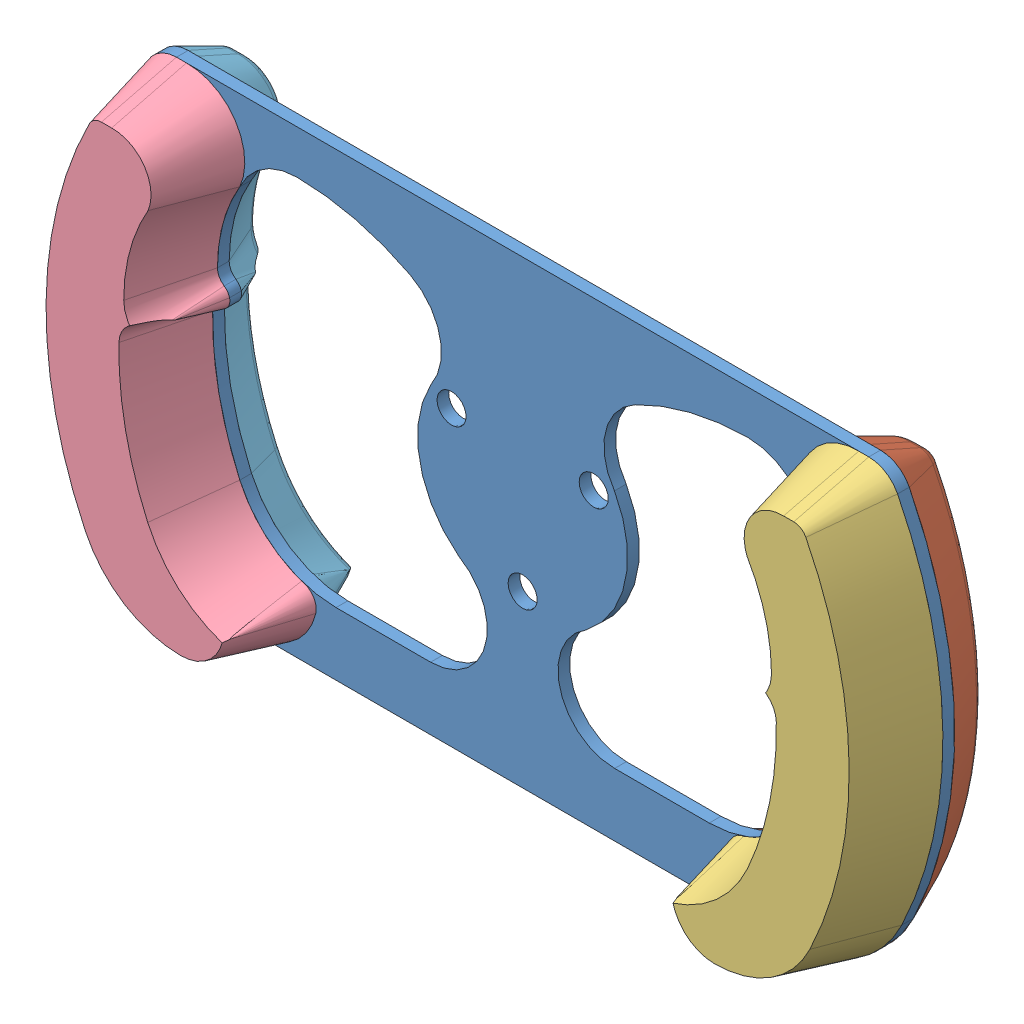
SolidWorks assembly FS2-ST-SW-A-V1, Steering Wheel, configuration Default. Lengths in mm.
Overall size (227.66 124.53 37.28).
5 component instances, 5 part files, 4 mates.
Components (placement in the parent):
- FS2-ST-SW-P-0001-V2, Steering Wheel center Structure-1: FS2-ST-SW-P-0001-V2, Steering Wheel center Structure [Default] at (175.0227 413.5967 334.3199) size (227.66 124.53 3.17)
- FS2-ST-SW-P-0002-V2, Front Grip-1: FS2-ST-SW-P-0002-V2, Front Grip [Default] at (175.0227 413.5967 334.3199) x (-1 0 0) z (0 0 -1) size (57.93 124.53 14.02)
- FS2-ST-SW-P-0003-V2, Back Grip-1: FS2-ST-SW-P-0003-V2, Back Grip [Default] at origin size (57.93 124.53 20.48)
- MirrorFS2-ST-SW-P-0003-V2, Back Grip-2: MirrorFS2-ST-SW-P-0003-V2, Back Grip [Default] at (350.0454 0 0) x (-1 0 0) z (0 0 -1) size (57.93 124.53 20.48)
- MirrorFS2-ST-SW-P-0002-V2, Front Grip-3: MirrorFS2-ST-SW-P-0002-V2, Front Grip [Default] at (175.0227 413.5967 334.3199) size (57.93 124.53 14.02)
Mates (geometry in assembly coordinates):
- InPlace1: in place: plane of ? through (175.0227 413.5967 334.3199) normal (0 0 -1); plane of ? through (0 0 334.3199) normal (0 0 -1); moOrthogonalPlaneRef_w of ? through (175.0227 413.5967 334.3199) normal (0 0 -1); plane of ? through (0 0 334.3199) normal (0 1 0); plane of ? through (175.0227 413.5967 334.3199) normal (0 0 -1); plane of ? through (0 0 334.3199) normal (-1 0 0); plane of ? through (175.0227 413.5967 334.3199) normal (0 0 -1); unknown of FS2-ST-SW-P-0002-V2, Front Grip-1
- Coincident1: coincident aligned: plane of FS2-ST-SW-P-0001-V2, Steering Wheel center Structure-1; plane of FS2-ST-SW-P-0002-V2, Front Grip-1
- Coincident2: coincident aligned: moOrthogonalPlaneRef_w of FS2-ST-SW-P-0001-V2, Steering Wheel center Structure-1 through (175.0227 413.5967 334.3199) normal (0 1 0); plane of FS2-ST-SW-P-0002-V2, Front Grip-1 through (175.0227 413.5967 334.3199) normal (0 1 0)
- Coincident3: coincident anti-aligned: moOrthogonalPlaneRef_w of FS2-ST-SW-P-0001-V2, Steering Wheel center Structure-1 through (175.0227 413.5967 334.3199) normal (1 0 0); plane of FS2-ST-SW-P-0002-V2, Front Grip-1 through (175.0227 413.5967 334.3199) normal (-1 0 0)
